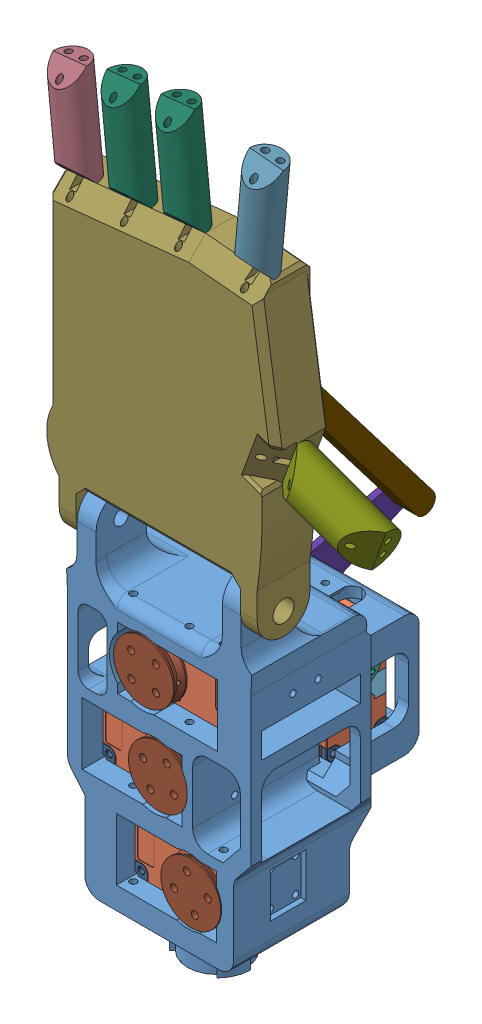
SolidWorks assembly Assemblage-total, configuration Default. Lengths in mm.
Overall size (552.25 411.47 150.47).
116 component instances, 18 part files, 42 mates.
Components (placement in the parent):
- FOREARM1-1: FOREARM1 [Default] at (-6.0593 113.608 167.3563) size (106 183 95)
- XL-430_new-1: XL-430_new [Default] at (-14.0593 148.358 196.3563) x (0 1 0) z (0 0 1) size (28.5 46.5 40.9)
  - XL-430_new.stp-1: XL-430_new.stp [Default] at origin size (28.5 46.5 40.9)
    - DC11_A01_DUMMY.stp-1: DC11_A01_DUMMY.stp [Default] at origin size (28.5 46.5 37.9)
    - DX124_SCREW-COVER.stp-1: DX124_SCREW-COVER.stp [Default] at (11.75 0 13.7) x (-1 0 0) z (0 1 0) size (3.5 30.65 3.5)
    - B3B-EH.stp-1: B3B-EH.stp [Default] at (10.15 -14.1 -3.8) x (0 -1 0) z (1 0 0) size (10 9.2 3.8)
    - B3B-EH.stp-2: B3B-EH.stp [Default] at (-10.15 -14.1 -3.8) x (0 1 0) z (-1 0 0) size (10 9.2 3.8)
    - DC11_A01_CASE_CVR_DUMMY.stp-1: DC11_A01_CASE_CVR_DUMMY.stp [Default] at origin size (28.3 17.62 8.31)
    - DC11_A01_IDLER_DUMMY.stp-1: DC11_A01_IDLER_DUMMY.stp [Default] at (0 0 -19) x (1 0 0) z (0 1 0) size (20.5 3.5 20.5)
    - DC11_A01_IDLER_CAP_DUMMY.stp-1: DC11_A01_IDLER_CAP_DUMMY.stp [Default] at (0 0 -18.8) x (1 0 0) z (0 -1 0) size (10.1 5.2 10.37)
    - DC11_A01_IDLER_SCREW.stp-1: DC11_A01_IDLER_SCREW.stp [Default] at (0 0 -15.1) x (-1 0 0) z (0 -1 0) size (5 5.01 5)
    - FHS_M2_5X10.stp-1: FHS_M2_5X10.stp [Default] at (11 8 12.95) x (-1 0 0) z (0 1 0) size (5 10.01 5)
    - FHS_M2_5X10.stp-2: FHS_M2_5X10.stp [Default] at (-11 8 12.95) x (-1 0 0) z (0 1 0) size (5 10.01 5)
    - FHS_M2_5X10.stp-3: FHS_M2_5X10.stp [Default] at (-11 -32 12.95) x (-1 0 0) z (0 1 0) size (5 10.01 5)
    - FHS_M2_5X10.stp-4: FHS_M2_5X10.stp [Default] at (11 -32 12.95) x (-1 0 0) z (0 1 0) size (5 10.01 5)
    - FHS_M2_5X10.stp-5: FHS_M2_5X10.stp [Default] at (-11 8 -12.95) x (1 0 0) z (0 1 0) size (5 10.01 5)
    - FHS_M2_5X10.stp-6: FHS_M2_5X10.stp [Default] at (11 8 -12.95) x (1 0 0) z (0 1 0) size (5 10.01 5)
    - FHS_M2_5X10.stp-7: FHS_M2_5X10.stp [Default] at (-11 -32 -12.95) x (1 0 0) z (0 1 0) size (5 10.01 5)
    - FHS_M2_5X10.stp-8: FHS_M2_5X10.stp [Default] at (11 -32 -12.95) x (1 0 0) z (0 1 0) size (5 10.01 5)
    - DC11_A01_SPACER_DUMMY.stp-1: DC11_A01_SPACER_DUMMY.stp [Default] at (11 8 14.2) x (-1 0 0) z (0 0 1) size (6.5 6.5 3.9)
    - DC11_A01_SPACER_DUMMY.stp-2: DC11_A01_SPACER_DUMMY.stp [Default] at (-11 8 14.2) x (0 -1 0) z (0 0 1) size (6.5 6.5 3.9)
    - DC11_A01_SPACER_DUMMY.stp-3: DC11_A01_SPACER_DUMMY.stp [Default] at (-11 -32 14.2) x (-1 0 0) z (0 0 1) size (6.5 6.5 3.9)
    - DC11_A01_SPACER_DUMMY.stp-4: DC11_A01_SPACER_DUMMY.stp [Default] at (11 -32 14.2) x (0 1 0) z (0 0 1) size (6.5 6.5 3.9)
    - DC11_A01_SPACER_DUMMY.stp-5: DC11_A01_SPACER_DUMMY.stp [Default] at (11 8 -14.2) x (0 -1 0) z (0 0 -1) size (6.5 6.5 3.9)
    - DC11_A01_SPACER_DUMMY.stp-6: DC11_A01_SPACER_DUMMY.stp [Default] at (-11 8 -14.2) x (1 0 0) z (0 0 -1) size (6.5 6.5 3.9)
    - DC11_A01_SPACER_DUMMY.stp-7: DC11_A01_SPACER_DUMMY.stp [Default] at (11 -32 -14.2) x (-1 0 0) z (0 0 -1) size (6.5 6.5 3.9)
    - DC11_A01_SPACER_DUMMY.stp-8: DC11_A01_SPACER_DUMMY.stp [Default] at (-11 -32 -14.2) x (0 1 0) z (0 0 -1) size (6.5 6.5 3.9)
- Poulie-1: Poulie [Défaut] at (-14.0593 148.358 218.5063) x (0.713426 -0.70073 0) z (0 0 -1) size (28.5 28.5 8.57)
- XL-430_new-2: XL-430_new [Default] at (-6.8793 108.858 196.3563) x (0 -1 0) z (0 0 1) size (28.5 46.5 40.9)
  - XL-430_new.stp-1: XL-430_new.stp [Default] at origin size (28.5 46.5 40.9)
    - DC11_A01_DUMMY.stp-1: DC11_A01_DUMMY.stp [Default] at origin size (28.5 46.5 37.9)
    - DX124_SCREW-COVER.stp-1: DX124_SCREW-COVER.stp [Default] at (11.75 0 13.7) x (-1 0 0) z (0 1 0) size (3.5 30.65 3.5)
    - B3B-EH.stp-1: B3B-EH.stp [Default] at (10.15 -14.1 -3.8) x (0 -1 0) z (1 0 0) size (10 9.2 3.8)
    - B3B-EH.stp-2: B3B-EH.stp [Default] at (-10.15 -14.1 -3.8) x (0 1 0) z (-1 0 0) size (10 9.2 3.8)
    - DC11_A01_CASE_CVR_DUMMY.stp-1: DC11_A01_CASE_CVR_DUMMY.stp [Default] at origin size (28.3 17.62 8.31)
    - DC11_A01_IDLER_DUMMY.stp-1: DC11_A01_IDLER_DUMMY.stp [Default] at (0 0 -19) x (1 0 0) z (0 1 0) size (20.5 3.5 20.5)
    - DC11_A01_IDLER_CAP_DUMMY.stp-1: DC11_A01_IDLER_CAP_DUMMY.stp [Default] at (0 0 -18.8) x (1 0 0) z (0 -1 0) size (10.1 5.2 10.37)
    - DC11_A01_IDLER_SCREW.stp-1: DC11_A01_IDLER_SCREW.stp [Default] at (0 0 -15.1) x (-1 0 0) z (0 -1 0) size (5 5.01 5)
    - FHS_M2_5X10.stp-1: FHS_M2_5X10.stp [Default] at (11 8 12.95) x (-1 0 0) z (0 1 0) size (5 10.01 5)
    - FHS_M2_5X10.stp-2: FHS_M2_5X10.stp [Default] at (-11 8 12.95) x (-1 0 0) z (0 1 0) size (5 10.01 5)
    - FHS_M2_5X10.stp-3: FHS_M2_5X10.stp [Default] at (-11 -32 12.95) x (-1 0 0) z (0 1 0) size (5 10.01 5)
    - FHS_M2_5X10.stp-4: FHS_M2_5X10.stp [Default] at (11 -32 12.95) x (-1 0 0) z (0 1 0) size (5 10.01 5)
    - FHS_M2_5X10.stp-5: FHS_M2_5X10.stp [Default] at (-11 8 -12.95) x (1 0 0) z (0 1 0) size (5 10.01 5)
    - FHS_M2_5X10.stp-6: FHS_M2_5X10.stp [Default] at (11 8 -12.95) x (1 0 0) z (0 1 0) size (5 10.01 5)
    - FHS_M2_5X10.stp-7: FHS_M2_5X10.stp [Default] at (-11 -32 -12.95) x (1 0 0) z (0 1 0) size (5 10.01 5)
    - FHS_M2_5X10.stp-8: FHS_M2_5X10.stp [Default] at (11 -32 -12.95) x (1 0 0) z (0 1 0) size (5 10.01 5)
    - DC11_A01_SPACER_DUMMY.stp-1: DC11_A01_SPACER_DUMMY.stp [Default] at (11 8 14.2) x (-1 0 0) z (0 0 1) size (6.5 6.5 3.9)
    - DC11_A01_SPACER_DUMMY.stp-2: DC11_A01_SPACER_DUMMY.stp [Default] at (-11 8 14.2) x (0 -1 0) z (0 0 1) size (6.5 6.5 3.9)
    - DC11_A01_SPACER_DUMMY.stp-3: DC11_A01_SPACER_DUMMY.stp [Default] at (-11 -32 14.2) x (-1 0 0) z (0 0 1) size (6.5 6.5 3.9)
    - DC11_A01_SPACER_DUMMY.stp-4: DC11_A01_SPACER_DUMMY.stp [Default] at (11 -32 14.2) x (0 1 0) z (0 0 1) size (6.5 6.5 3.9)
    - DC11_A01_SPACER_DUMMY.stp-5: DC11_A01_SPACER_DUMMY.stp [Default] at (11 8 -14.2) x (0 -1 0) z (0 0 -1) size (6.5 6.5 3.9)
    - DC11_A01_SPACER_DUMMY.stp-6: DC11_A01_SPACER_DUMMY.stp [Default] at (-11 8 -14.2) x (1 0 0) z (0 0 -1) size (6.5 6.5 3.9)
    - DC11_A01_SPACER_DUMMY.stp-7: DC11_A01_SPACER_DUMMY.stp [Default] at (11 -32 -14.2) x (-1 0 0) z (0 0 -1) size (6.5 6.5 3.9)
    - DC11_A01_SPACER_DUMMY.stp-8: DC11_A01_SPACER_DUMMY.stp [Default] at (-11 -32 -14.2) x (0 1 0) z (0 0 -1) size (6.5 6.5 3.9)
- Poulie-2: Poulie [Défaut] at (-6.8793 108.858 218.6063) x (0.881342 -0.472478 0) z (0 0 -1) size (28.5 28.5 8.57)
- XL-430_new-3: XL-430_new [Default] at (9.3507 69.358 197.3307) x (0 -1 0) z (0 0 1) size (28.5 46.5 40.9)
  - XL-430_new.stp-1: XL-430_new.stp [Default] at origin size (28.5 46.5 40.9)
    - DC11_A01_DUMMY.stp-1: DC11_A01_DUMMY.stp [Default] at origin size (28.5 46.5 37.9)
    - DX124_SCREW-COVER.stp-1: DX124_SCREW-COVER.stp [Default] at (11.75 0 13.7) x (-1 0 0) z (0 1 0) size (3.5 30.65 3.5)
    - B3B-EH.stp-1: B3B-EH.stp [Default] at (10.15 -14.1 -3.8) x (0 -1 0) z (1 0 0) size (10 9.2 3.8)
    - B3B-EH.stp-2: B3B-EH.stp [Default] at (-10.15 -14.1 -3.8) x (0 1 0) z (-1 0 0) size (10 9.2 3.8)
    - DC11_A01_CASE_CVR_DUMMY.stp-1: DC11_A01_CASE_CVR_DUMMY.stp [Default] at origin size (28.3 17.62 8.31)
    - DC11_A01_IDLER_DUMMY.stp-1: DC11_A01_IDLER_DUMMY.stp [Default] at (0 0 -19) x (1 0 0) z (0 1 0) size (20.5 3.5 20.5)
    - DC11_A01_IDLER_CAP_DUMMY.stp-1: DC11_A01_IDLER_CAP_DUMMY.stp [Default] at (0 0 -18.8) x (1 0 0) z (0 -1 0) size (10.1 5.2 10.37)
    - DC11_A01_IDLER_SCREW.stp-1: DC11_A01_IDLER_SCREW.stp [Default] at (0 0 -15.1) x (-1 0 0) z (0 -1 0) size (5 5.01 5)
    - FHS_M2_5X10.stp-1: FHS_M2_5X10.stp [Default] at (11 8 12.95) x (-1 0 0) z (0 1 0) size (5 10.01 5)
    - FHS_M2_5X10.stp-2: FHS_M2_5X10.stp [Default] at (-11 8 12.95) x (-1 0 0) z (0 1 0) size (5 10.01 5)
    - FHS_M2_5X10.stp-3: FHS_M2_5X10.stp [Default] at (-11 -32 12.95) x (-1 0 0) z (0 1 0) size (5 10.01 5)
    - FHS_M2_5X10.stp-4: FHS_M2_5X10.stp [Default] at (11 -32 12.95) x (-1 0 0) z (0 1 0) size (5 10.01 5)
    - FHS_M2_5X10.stp-5: FHS_M2_5X10.stp [Default] at (-11 8 -12.95) x (1 0 0) z (0 1 0) size (5 10.01 5)
    - FHS_M2_5X10.stp-6: FHS_M2_5X10.stp [Default] at (11 8 -12.95) x (1 0 0) z (0 1 0) size (5 10.01 5)
    - FHS_M2_5X10.stp-7: FHS_M2_5X10.stp [Default] at (-11 -32 -12.95) x (1 0 0) z (0 1 0) size (5 10.01 5)
    - FHS_M2_5X10.stp-8: FHS_M2_5X10.stp [Default] at (11 -32 -12.95) x (1 0 0) z (0 1 0) size (5 10.01 5)
    - DC11_A01_SPACER_DUMMY.stp-1: DC11_A01_SPACER_DUMMY.stp [Default] at (11 8 14.2) x (-1 0 0) z (0 0 1) size (6.5 6.5 3.9)
    - DC11_A01_SPACER_DUMMY.stp-2: DC11_A01_SPACER_DUMMY.stp [Default] at (-11 8 14.2) x (0 -1 0) z (0 0 1) size (6.5 6.5 3.9)
    - DC11_A01_SPACER_DUMMY.stp-3: DC11_A01_SPACER_DUMMY.stp [Default] at (-11 -32 14.2) x (-1 0 0) z (0 0 1) size (6.5 6.5 3.9)
    - DC11_A01_SPACER_DUMMY.stp-4: DC11_A01_SPACER_DUMMY.stp [Default] at (11 -32 14.2) x (0 1 0) z (0 0 1) size (6.5 6.5 3.9)
    - DC11_A01_SPACER_DUMMY.stp-5: DC11_A01_SPACER_DUMMY.stp [Default] at (11 8 -14.2) x (0 -1 0) z (0 0 -1) size (6.5 6.5 3.9)
    - DC11_A01_SPACER_DUMMY.stp-6: DC11_A01_SPACER_DUMMY.stp [Default] at (-11 8 -14.2) x (1 0 0) z (0 0 -1) size (6.5 6.5 3.9)
    - DC11_A01_SPACER_DUMMY.stp-7: DC11_A01_SPACER_DUMMY.stp [Default] at (11 -32 -14.2) x (-1 0 0) z (0 0 -1) size (6.5 6.5 3.9)
    - DC11_A01_SPACER_DUMMY.stp-8: DC11_A01_SPACER_DUMMY.stp [Default] at (-11 -32 -14.2) x (0 1 0) z (0 0 -1) size (6.5 6.5 3.9)
- Poulie-3: Poulie [Défaut] at (9.3507 69.358 219.4807) x (0.230585 -0.973052 0) z (0 0 -1) size (28.5 28.5 8.57)
- XL-430_new-5: XL-430_new [Default] at (-3.8695 128.638 147.6063) x (0 0 1) z (-1 0 0) size (28.5 46.5 40.9)
  - XL-430_new.stp-1: XL-430_new.stp [Default] at origin size (28.5 46.5 40.9)
    - DC11_A01_DUMMY.stp-1: DC11_A01_DUMMY.stp [Default] at origin size (28.5 46.5 37.9)
    - DX124_SCREW-COVER.stp-1: DX124_SCREW-COVER.stp [Default] at (11.75 0 13.7) x (-1 0 0) z (0 1 0) size (3.5 30.65 3.5)
    - B3B-EH.stp-1: B3B-EH.stp [Default] at (10.15 -14.1 -3.8) x (0 -1 0) z (1 0 0) size (10 9.2 3.8)
    - B3B-EH.stp-2: B3B-EH.stp [Default] at (-10.15 -14.1 -3.8) x (0 1 0) z (-1 0 0) size (10 9.2 3.8)
    - DC11_A01_CASE_CVR_DUMMY.stp-1: DC11_A01_CASE_CVR_DUMMY.stp [Default] at origin size (28.3 17.62 8.31)
    - DC11_A01_IDLER_DUMMY.stp-1: DC11_A01_IDLER_DUMMY.stp [Default] at (0 0 -19) x (1 0 0) z (0 1 0) size (20.5 3.5 20.5)
    - DC11_A01_IDLER_CAP_DUMMY.stp-1: DC11_A01_IDLER_CAP_DUMMY.stp [Default] at (0 0 -18.8) x (1 0 0) z (0 -1 0) size (10.1 5.2 10.37)
    - DC11_A01_IDLER_SCREW.stp-1: DC11_A01_IDLER_SCREW.stp [Default] at (0 0 -15.1) x (-1 0 0) z (0 -1 0) size (5 5.01 5)
    - FHS_M2_5X10.stp-1: FHS_M2_5X10.stp [Default] at (11 8 12.95) x (-1 0 0) z (0 1 0) size (5 10.01 5)
    - FHS_M2_5X10.stp-2: FHS_M2_5X10.stp [Default] at (-11 8 12.95) x (-1 0 0) z (0 1 0) size (5 10.01 5)
    - FHS_M2_5X10.stp-3: FHS_M2_5X10.stp [Default] at (-11 -32 12.95) x (-1 0 0) z (0 1 0) size (5 10.01 5)
    - FHS_M2_5X10.stp-4: FHS_M2_5X10.stp [Default] at (11 -32 12.95) x (-1 0 0) z (0 1 0) size (5 10.01 5)
    - FHS_M2_5X10.stp-5: FHS_M2_5X10.stp [Default] at (-11 8 -12.95) x (1 0 0) z (0 1 0) size (5 10.01 5)
    - FHS_M2_5X10.stp-6: FHS_M2_5X10.stp [Default] at (11 8 -12.95) x (1 0 0) z (0 1 0) size (5 10.01 5)
    - FHS_M2_5X10.stp-7: FHS_M2_5X10.stp [Default] at (-11 -32 -12.95) x (1 0 0) z (0 1 0) size (5 10.01 5)
    - FHS_M2_5X10.stp-8: FHS_M2_5X10.stp [Default] at (11 -32 -12.95) x (1 0 0) z (0 1 0) size (5 10.01 5)
    - DC11_A01_SPACER_DUMMY.stp-1: DC11_A01_SPACER_DUMMY.stp [Default] at (11 8 14.2) x (-1 0 0) z (0 0 1) size (6.5 6.5 3.9)
    - DC11_A01_SPACER_DUMMY.stp-2: DC11_A01_SPACER_DUMMY.stp [Default] at (-11 8 14.2) x (0 -1 0) z (0 0 1) size (6.5 6.5 3.9)
    - DC11_A01_SPACER_DUMMY.stp-3: DC11_A01_SPACER_DUMMY.stp [Default] at (-11 -32 14.2) x (-1 0 0) z (0 0 1) size (6.5 6.5 3.9)
    - DC11_A01_SPACER_DUMMY.stp-4: DC11_A01_SPACER_DUMMY.stp [Default] at (11 -32 14.2) x (0 1 0) z (0 0 1) size (6.5 6.5 3.9)
    - DC11_A01_SPACER_DUMMY.stp-5: DC11_A01_SPACER_DUMMY.stp [Default] at (11 8 -14.2) x (0 -1 0) z (0 0 -1) size (6.5 6.5 3.9)
    - DC11_A01_SPACER_DUMMY.stp-6: DC11_A01_SPACER_DUMMY.stp [Default] at (-11 8 -14.2) x (1 0 0) z (0 0 -1) size (6.5 6.5 3.9)
    - DC11_A01_SPACER_DUMMY.stp-7: DC11_A01_SPACER_DUMMY.stp [Default] at (11 -32 -14.2) x (-1 0 0) z (0 0 -1) size (6.5 6.5 3.9)
    - DC11_A01_SPACER_DUMMY.stp-8: DC11_A01_SPACER_DUMMY.stp [Default] at (-11 -32 -14.2) x (0 1 0) z (0 0 -1) size (6.5 6.5 3.9)
- main-2: main [Default] at (-48.974 209.608 210.3563) size (109.01 152 41.5)
- bas petit doigt-2: bas petit doigt [Default] at (-46.0384 179.0118 214.8563) size (257.86 357.39 16)
- bas annulaire+index doigt-1: bas annulaire+index doigt [Default] at (8.9227 186.0718 214.8563) x (0.980974 -0.19414 0) z (0 0 1) size (257.86 357.39 16)
- bas majeur doigt-3: bas majeur doigt [Default] at (5.2983 186.8787 214.8563) size (257.86 357.39 16)
- bas majeur doigt-4: bas majeur doigt [Default] at (-20.4778 184.2056 214.8563) size (257.86 357.39 16)
- bas pouce-1: bas pouce [Default] at (228.384 182.9779 212.8563) x (0.437126 0.899401 0) z (0 0 1) size (257.86 357.39 20)
- Mécanisme poignet 1-1: Mécanisme poignet 1 [Défaut] at (-26.0195 128.638 147.6063) x (0 -0.949748 -0.313016) z (1 0 0) size (28.5 84.3 8.57)
- Mécanisme poignet 2-2: Mécanisme poignet 2 [Défaut] at (-21.1445 263.2644 175.6413) x (0 -0.794362 -0.607445) z (1 0 0) size (184 10 25)
Mates (geometry in assembly coordinates):
- Coaxiale1: concentric aligned: circle of FOREARM1-1; circle of hand-2-1
- Coïncidente1: coincident anti-aligned: plane of FOREARM1-1 through (-14.0593 148.358 177.3563) normal (0 0 1); plane of XL-430_new-1/XL-430_new.stp-1/DC11_A01_IDLER_DUMMY.stp-1 through (-14.0593 148.358 177.3563) normal (0 0 -1)
- Coaxiale2: concentric aligned: circle of FOREARM1-1; circle of XL-430_new-1/XL-430_new.stp-1/DC11_A01_IDLER_DUMMY.stp-1
- Parallèle1: parallel aligned: line of FOREARM1-1 through (-25.8093 133.608 222.3563) axis (1 0 0); line of XL-430_new-1/XL-430_new.stp-1/DC11_A01_DUMMY.stp-1 through (-18.8093 134.408 213.3563) axis (1 0 0)
- Coaxiale3: concentric anti-aligned: circle of XL-430_new-1/XL-430_new.stp-1/DC11_A01_DUMMY.stp-1; circle of Poulie-1
- Coïncidente5: coincident anti-aligned: plane of XL-430_new-1/XL-430_new.stp-1/DC11_A01_DUMMY.stp-1 through (-14.0593 148.358 217.2563) normal (0 0 1); plane of Poulie-1 through (-14.0593 148.358 217.2563) normal (0 0 -1)
- Coaxiale4: concentric aligned: circle of FOREARM1-1; circle of XL-430_new-2/XL-430_new.stp-1/DC11_A01_IDLER_DUMMY.stp-1
- Coïncidente6: coincident anti-aligned: plane of FOREARM1-1 through (-6.8793 108.858 177.3563) normal (0 0 1); plane of XL-430_new-2/XL-430_new.stp-1/DC11_A01_IDLER_DUMMY.stp-1 through (-6.8793 108.858 177.3563) normal (0 0 -1)
- Parallèle5: parallel anti-aligned: plane of FOREARM1-1 through (-42.6293 123.608 232.3563) normal (0 -1 0); plane of XL-430_new-2/XL-430_new.stp-1/DC11_A01_DUMMY.stp-1 through (2.3707 123.108 213.3563) normal (0 1 0)
- Coaxiale5: concentric anti-aligned: circle of XL-430_new-2/XL-430_new.stp-1/DC11_A01_DUMMY.stp-1; circle of Poulie-2
- Verrouiller2: lock: unknown of FOREARM1-1; unknown of XL-430_new-3
- Coaxiale6: concentric aligned: circle of FOREARM1-1; circle of XL-430_new-3/XL-430_new.stp-1/DC11_A01_IDLER_DUMMY.stp-1
- Coaxiale7: concentric anti-aligned: circle of XL-430_new-3/XL-430_new.stp-1/DC11_A01_DUMMY.stp-1; circle of Poulie-3
- Coïncidente8: coincident anti-aligned: plane of XL-430_new-3/XL-430_new.stp-1/DC11_A01_DUMMY.stp-1 through (9.3507 69.358 218.2307) normal (0 0 1); plane of Poulie-3 through (9.3507 69.358 218.2307) normal (0 0 -1)
- Coïncidente11: coincident anti-aligned: plane of XL-430_new-2/XL-430_new.stp-1/DC11_A01_DUMMY.stp-1 through (-6.8793 108.858 215.3563) normal (0 0 1); plane of Poulie-2 through (-6.8793 108.858 215.3563) normal (0 0 -1)
- Coïncidente14: coincident: plane of FOREARM1-1 through (17.5107 113.608 167.3563) normal (-1 0 0); plane of XL-430_new-5/XL-430_new.stp-1/DC11_A01_DUMMY.stp-1 through (13.1305 128.638 147.6063) normal (1 0 0)
- Parallèle8: parallel anti-aligned: line of FOREARM1-1 through (17.5107 93.388 132.3563) axis (0 0 1); line of XL-430_new-5/XL-430_new.stp-1/DC11_A01_DUMMY.stp-1 through (12.8305 93.388 155.0563) axis (0 0 -1)
- Coaxiale9: concentric: circle of FOREARM1-1; circle of XL-430_new-5/XL-430_new.stp-1/DC11_A01_DUMMY.stp-1
- Coïncidente22: coincident anti-aligned: plane of FOREARM1-1 through (-59.0593 93.388 132.8563) normal (0 1 0); plane of XL-430_new-5/XL-430_new.stp-1/DC11_A01_DUMMY.stp-1 through (-20.8695 93.388 135.3563) normal (0 -1 0)
- Coaxiale10: concentric anti-aligned: circle of XL-430_new-5/XL-430_new.stp-1/DC11_A01_DUMMY.stp-1; circle of Poulie-4
- Coïncidente23: coincident anti-aligned: plane of XL-430_new-5/XL-430_new.stp-1/DC11_A01_DUMMY.stp-1 through (-24.7695 128.638 147.6063) normal (-1 0 0); plane of Poulie-4 through (-24.7695 128.638 147.6063) normal (1 0 0)
- Coaxiale11: concentric aligned: circle of FOREARM1-1; circle of main-1
- Coïncidente24: coincident anti-aligned: plane of FOREARM1-1 through (32.9407 207.108 127.3563) normal (1 0 0); plane of main-1 through (32.9407 208.7063 223.8318) normal (-1 0 0)
- Coaxiale12: concentric: circle of FOREARM1-1; circle of main-2
- Coïncidente25: coincident: plane of FOREARM1-1 through (-45.0593 207.108 127.3563) normal (-1 0 0); plane of main-2 through (-45.0593 209.608 222.8563) normal (1 0 0)
- Coïncidente26: coincident anti-aligned: plane of main-2 through (-36.8641 340.7979 222.8563) normal (0.091917 0.995767 0); plane of bas majeur doigt-2 through (30.6687 334.5641 214.8563) normal (-0.091917 -0.995767 0)
- Coïncidente28: coincident aligned: line of main-2 through (8.526 336.608 214.8563) axis (0.995767 -0.091917 0); line of bas majeur doigt-2 through (22.7026 335.2994 214.8563) axis (0.995767 -0.091917 0)
- Coïncidente33: coincident: plane of main-2 through (-61.3924 329.3572 222.8563) normal (-0.103151 0.994666 0); plane of bas petit doigt-2 through (-51.2514 330.4089 214.8563) normal (0.103151 -0.994666 0)
- Coïncidente34: coincident: line of main-2 through (-58.974 329.608 214.8563) axis (0.994666 0.103151 0); line of bas petit doigt-2 through (-59.2088 329.5837 214.8563) axis (0.994666 0.103151 0)
- Coïncidente35: coincident: plane of main-2 through (-36.8641 340.7979 222.8563) normal (0.091917 0.995767 0); plane of bas annulaire+index doigt-1 through (33.0848 334.341 214.8563) normal (-0.091917 -0.995767 0)
- Coïncidente36: coincident: line of main-2 through (8.526 336.608 214.8563) axis (0.995767 -0.091917 0); line of bas annulaire+index doigt-1 through (25.1187 335.0764 214.8563) axis (0.995767 -0.091917 0)
- Coïncidente37: coincident: plane of main-2 through (-61.3924 329.3572 222.8563) normal (-0.103151 0.994666 0); plane of bas majeur doigt-3 through (0.3461 335.7597 214.8563) normal (0.103151 -0.994666 0)
- Coïncidente38: coincident: line of main-2 through (-58.974 329.608 214.8563) axis (0.994666 0.103151 0); line of bas majeur doigt-3 through (-7.6112 334.9345 214.8563) axis (0.994666 0.103151 0)
- Coïncidente39: coincident: plane of main-2 through (-61.3924 329.3572 222.8563) normal (-0.103151 0.994666 0); plane of bas majeur doigt-4 through (-25.43 333.0866 214.8563) normal (0.103151 -0.994666 0)
- Coïncidente40: coincident: line of main-2 through (-58.974 329.608 214.8563) axis (0.994666 0.103151 0); line of bas majeur doigt-4 through (-33.3873 332.2614 214.8563) axis (0.994666 0.103151 0)
- Coïncidente41: coincident: plane of main-2 through (19.1616 184.8087 222.8563) normal (0.939693 -0.34202 0); plane of bas pouce-1 through (88.9015 244.8462 212.8563) normal (0.939693 -0.34202 0)
- Coïncidente43: coincident: line of main-2 through (50.026 269.608 212.8563) axis (-0.34202 -0.939693 0); line of bas pouce-1 through (43.8792 252.7196 212.8563) axis (0.34202 0.939693 0)
- Coïncidente44: coincident anti-aligned: plane of XL-430_new-5/XL-430_new.stp-1/DC11_A01_DUMMY.stp-1 through (-24.7695 128.638 147.6063) normal (-1 0 0); plane of Mécanisme poignet 1-1 through (-24.7695 128.638 147.6063) normal (1 0 0)
- Coaxiale13: concentric anti-aligned: circle of XL-430_new-5/XL-430_new.stp-1/DC11_A01_DUMMY.stp-1; circle of Mécanisme poignet 1-1
- Coïncidente49: coincident anti-aligned: plane of Mécanisme poignet 1-1 through (-26.2695 128.638 147.6063) normal (1 0 0); plane of Mécanisme poignet 2-2 through (-26.2695 287.108 191.8563) normal (-1 0 0)
- Coaxiale15: concentric anti-aligned: circle of Mécanisme poignet 1-1; circle of Mécanisme poignet 2-2
- Coaxiale16: concentric aligned: circle of main-2; circle of Mécanisme poignet 2-2
